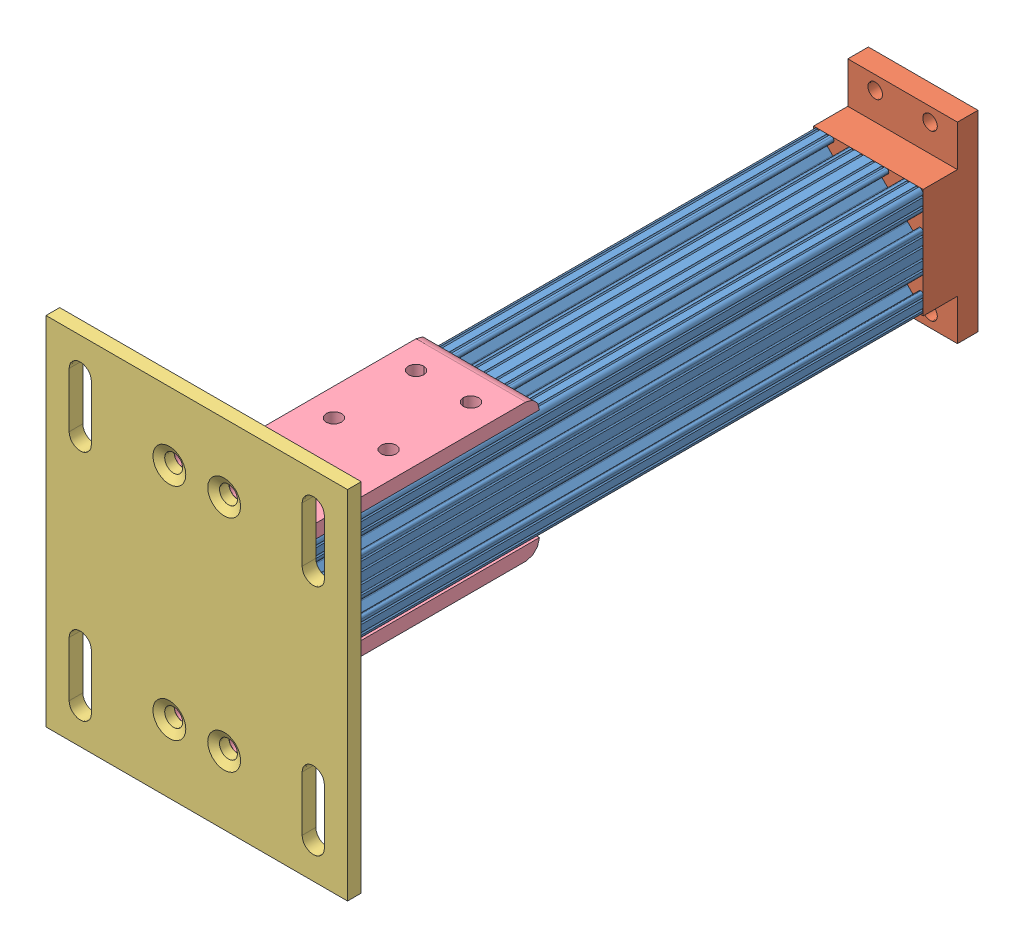
SolidWorks assembly breadboard support leg assembly 2020, configuration Default. Lengths in mm.
Overall size (139.7 165.1 336.55).
6 component instances, 4 part files, 6 mates.
Components (placement in the parent):
- 8020-2020-1: 8020-2020 [Default] at (-20.9287 -3.61 165.8964) size (50.8 50.8 304.8)
- breadboard support leg top bracket 2020-1: breadboard support leg top bracket 2020 [Default] at (-46.3287 21.79 -138.9036) x (1 0 0) z (0 1 0) size (50.8 25.4 88.9)
- 8020-2387-DEFAULT-1: 8020-2387-DEFAULT [Default] at (-4.6551 -4.8293 179.6168) x (1 0 0) z (0 1 0) size (139.7 133.35 165.1)
  - 8020-2387-DEFAULT_238708-1: 8020-2387-DEFAULT_238708 [Default] at (-67.1549 7.3704 27.8119) size (139.7 6.35 165.1)
  - 8020-2387-DEFAULT_238509-1: 8020-2387-DEFAULT_238509 [Default] at (9.1264 0.0214 49.7635) x (0 0 1) z (-1 0 0) size (50.8 127 50.8)
  - 8020-2387-DEFAULT_238509-2: 8020-2387-DEFAULT_238509 [Default] at (-41.6736 0.0214 -46.9187) x (0 0 -1) z (1 0 0) size (50.8 127 50.8)
Mates (geometry in assembly coordinates):
- Coincident1: coincident anti-aligned: plane of 8020-2020-1 through (-13.973 -28.9335 165.8964) normal (0 0 1); plane of 8020-2387-DEFAULT-1/8020-2387-DEFAULT_238708-1 through (-189.2902 -3.4068 165.8964) normal (0 0 -1)
- Coincident2: coincident anti-aligned: plane of 8020-2020-1 through (-26.1992 -29.01 -138.9036) normal (0 -1 0); plane of 8020-2387-DEFAULT-1/8020-2387-DEFAULT_238509-2 through (4.4713 -29.01 238.6681) normal (0 1 0)
- Coincident3: coincident aligned: plane of 8020-2020-1 through (-46.3287 -5.6783 -138.9036) normal (-1 0 0); plane of 8020-2387-DEFAULT-1/8020-2387-DEFAULT_238509-2 through (-46.3287 -38.833 238.6681) normal (-1 0 0)
- Coincident4: coincident: plane of 8020-2020-1 through (-13.973 -28.9335 -138.9036) normal (0 0 -1); plane of breadboard support leg top bracket 2020-1 through (-20.9287 -29.01 -138.9036) normal (0 0 1)
- Coincident7: coincident: plane of 8020-2020-1 through (-23.1388 21.79 -138.9036) normal (0 1 0); plane of breadboard support leg top bracket 2020-1 through (-46.3287 21.79 -164.3036) normal (0 1 0)
- Concentric2: concentric anti-aligned: circle of 8020-2020-1; circle of breadboard support leg top bracket 2020-1
